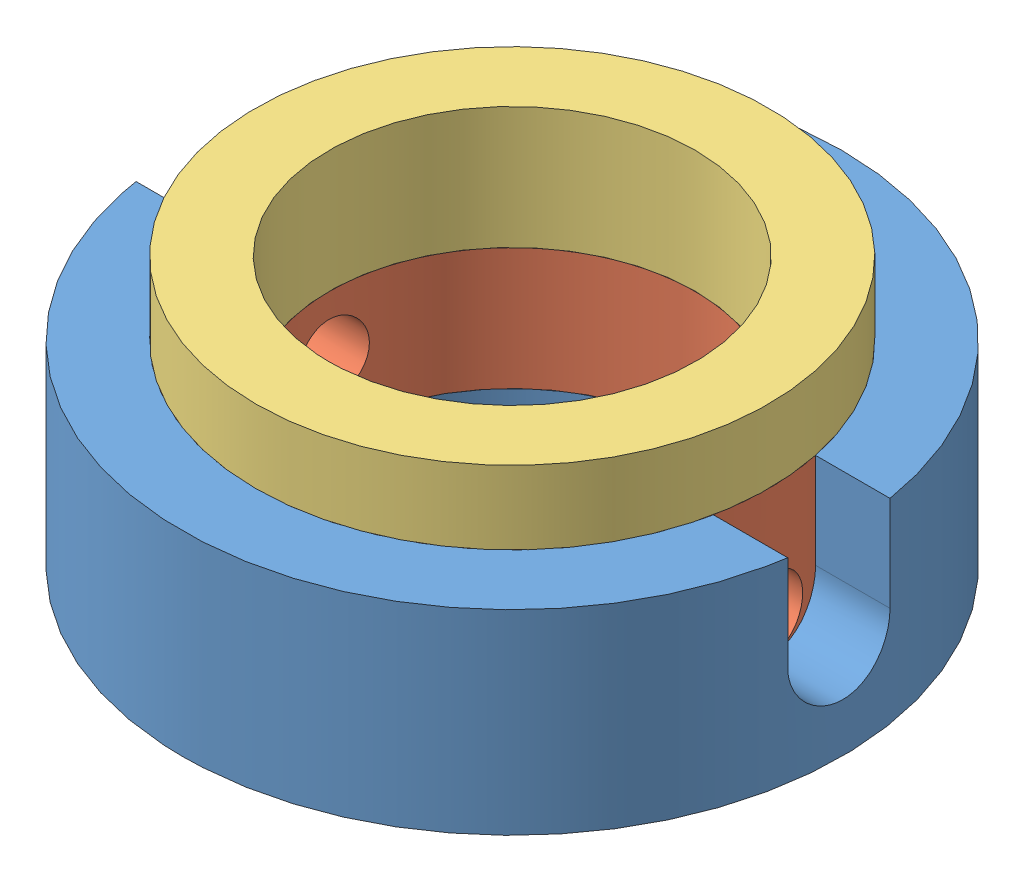
SolidWorks assembly 3D view, configuration Default. Lengths in mm.
Overall size (27 11 27).
3 component instances, 3 part files, 5 mates.
Components (placement in the parent):
- Bottom-1: Bottom [Default] at (0.6532 -0.2439 0) size (27 8 27)
- Inner bottom-1: Inner bottom [Default] at (0.6532 0.7561 0) size (21 7 21)
- Inner up-1: Inner up [Default] at (0.6532 5.7561 0) size (21 5 21)
Mates (geometry in assembly coordinates):
- Concentrico1: concentric aligned: circle of Bottom-1; circle of Inner bottom-1
- Coincidente1: coincident anti-aligned: plane of Bottom-1 through (0.6532 0.7561 0) normal (0 1 0); plane of Inner bottom-1 through (0.6532 0.7561 0) normal (0 -1 0)
- Concentrico2: concentric aligned: circle of Inner bottom-1; circle of Inner up-1
- Coincidente2: coincident aligned: plane of Inner bottom-1 through (0.6532 5.7561 0) normal (0 1 0); circle of Inner up-1
- Parallelo1: parallel aligned: line of Bottom-1 through (0.6532 -0.2439 13.5) axis (0 0 -1); line of Inner bottom-1 through (0.6532 0.7561 10.5) axis (0 0 -1)
